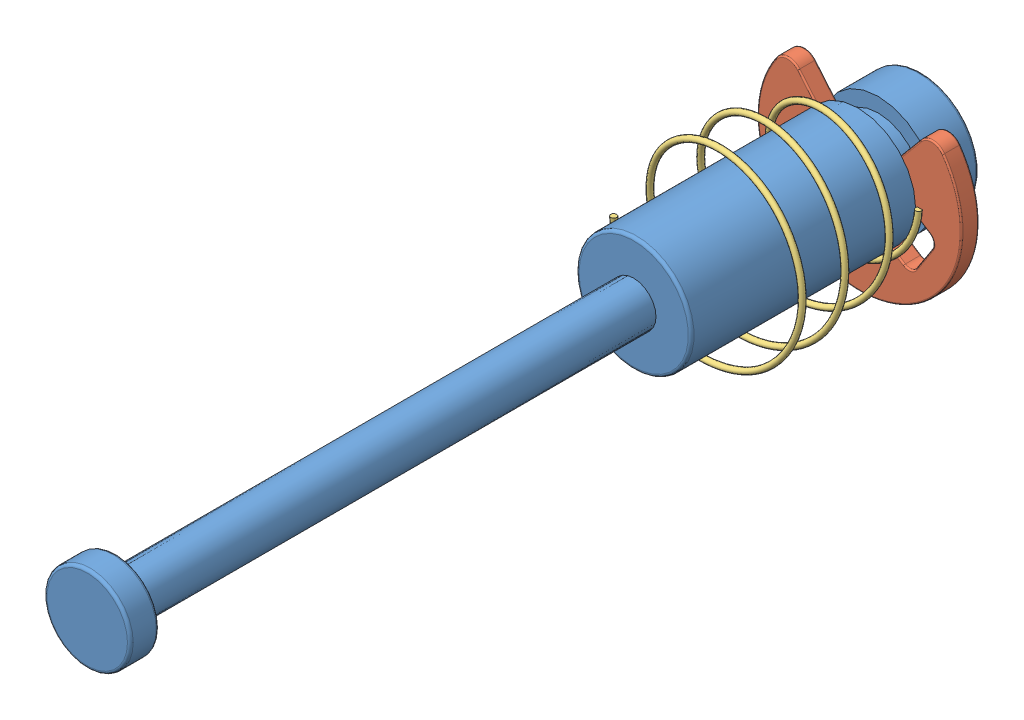
SolidWorks assembly Shaft Assem, configuration Default. Lengths in mm.
Overall size (7.1 6.76 29).
3 component instances, 3 part files, 5 mates.
Components (placement in the parent):
- Shaft-1: Shaft [Default] at origin size (4 4 29)
- Circlip-1: Circlip [Default] at (0 0 -8.45) size (7.1 5.79 0.6)
- Spring-1: Spring [Default] at (0 0 -2.3) x (-1 0 0) z (0 0 -1) size (6.3 6.5 5.85)
Mates (geometry in assembly coordinates):
- Coincident2: coordinate: point of Shaft-1
- Distance1: distance = 0.05 mm anti-aligned: plane of Shaft-1 through (0 2 -8.5) normal (0 0 1); plane of Circlip-1 through (0 0 -8.45) normal (0 0 -1)
- Coincident4: coincident anti-aligned: plane of Shaft-1 through (0 0 0) normal (1 0 0); plane of Spring-1 through (0 0 -2.3) normal (-1 0 0)
- Coincident5: coincident aligned: plane of Shaft-1 through (0 0 0) normal (0 1 0); plane of Spring-1 through (0 0 -2.3) normal (0 1 0)
- Distance2: distance = 2.3 mm anti-aligned: plane of Spring-1 through (0 0 -2.3) normal (0 0 -1); plane of Shaft-1 through (0 0 0) normal (0 0 1)
